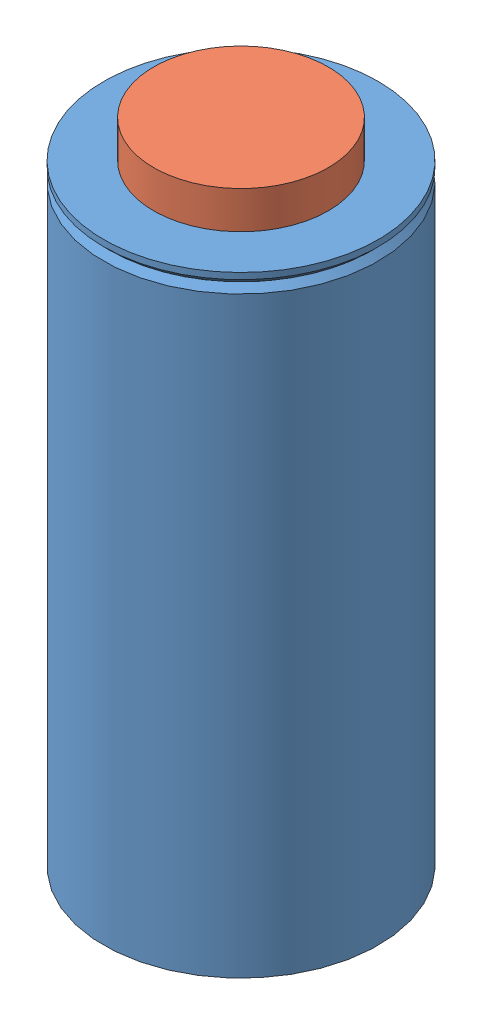
SolidWorks assembly Assem1, configuration Default. Lengths in mm.
Overall size (139.7 330.2 139.7).
2 component instances, 2 part files, 3 mates.
Components (placement in the parent):
- chamber sleeve-1: chamber sleeve [Default] at origin size (139.7 311.15 139.7)
- ablative impinging injector-1: ablative impinging injector [Default] x (0.948469 0 -0.31687) z (0.31687 0 0.948469) size (88.9 25.4 88.9)
Mates (geometry in assembly coordinates):
- Coincident1: coordinate: point of chamber sleeve-1
- Concentric1: concentric: cylinder of chamber sleeve-1 through (0 0 0) axis (0 -1 0) radius 69.85; cylinder of ablative impinging injector-1 through (0 0 0) axis (0 -1 0) radius 44.45
- Coincident2: coincident anti-aligned: plane of chamber sleeve-1 through (-69.85 6.35 0) normal (0 1 0); plane of ablative impinging injector-1 through (-42.1594 6.35 14.0849) normal (0 -1 0)
